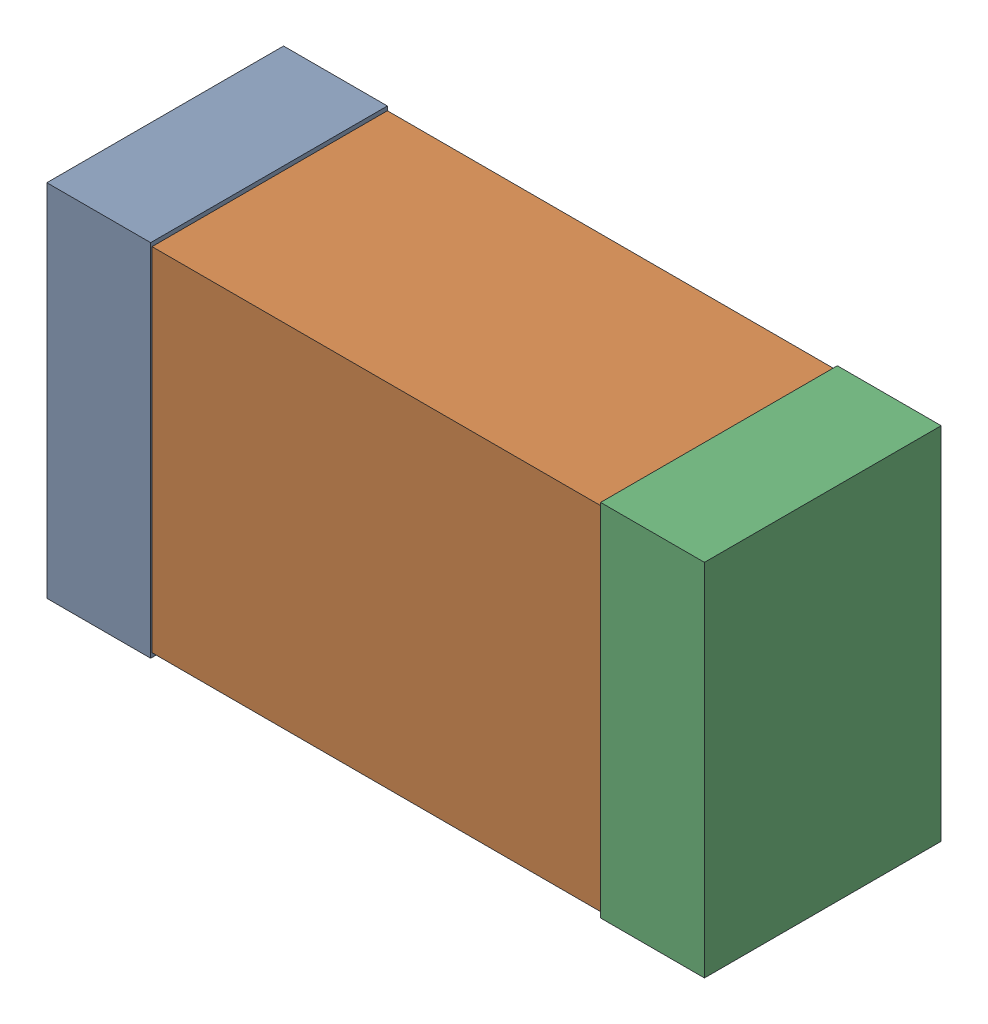
SolidWorks assembly C14_Motor_8Kanaloa_v2.0.0_Motor, configuration Default. Lengths in mm.
Overall size (2.38 1.3 0.85).
6 component instances, 2 part files, 0 mates.
Components (placement in the parent):
- 352877648-1: 352877648 [Default] at (119.408 138.557 0) size (0.38 1.3 0.85)
  - Extruded_14-1: Extruded_14 [Default] at origin size (0.38 1.3 0.85)
- 352877392-1: 352877392 [Default] at (120.408 138.557 0) size (2.2 1.27 0.85)
  - Extruded_15-1: Extruded_15 [Default] at origin size (2.2 1.27 0.85)
- 352877648-2: 352877648 [Default] at (121.408 138.557 0) size (0.38 1.3 0.85)
  - Extruded_14-1: Extruded_14 [Default] at origin size (0.38 1.3 0.85)
